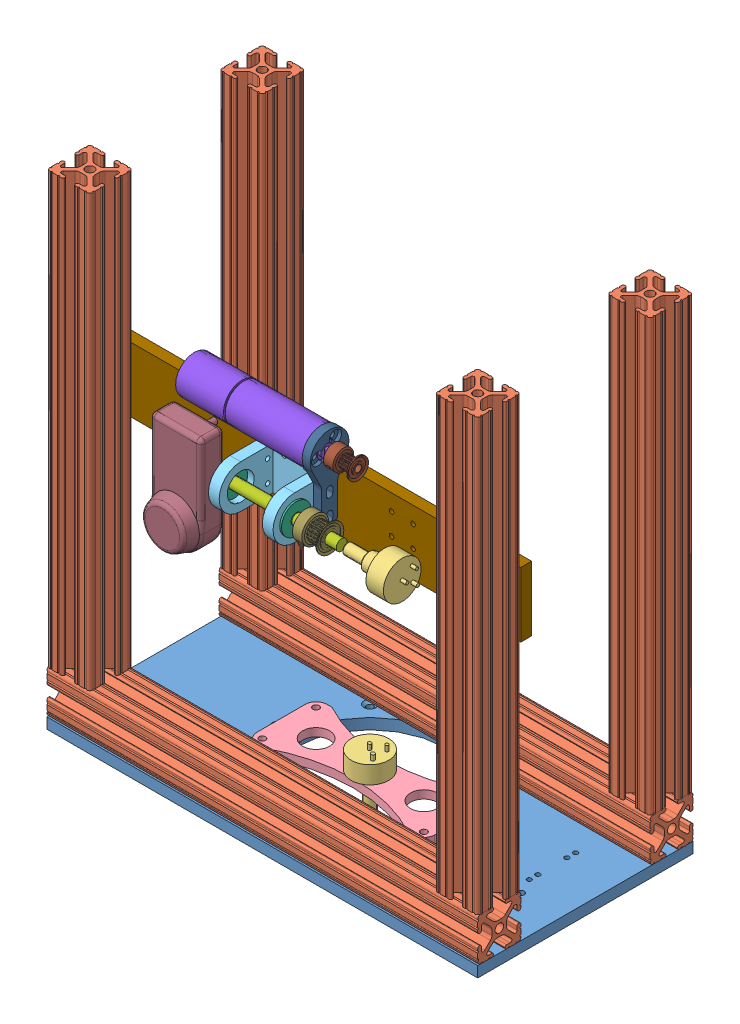
SolidWorks assembly body-frame, configuration Default. Lengths in mm.
Overall size (254 296.86 139.7).
21 component instances, 13 part files, 26 mates.
Components (placement in the parent):
- y01body-bottom-1: y01body-bottom [Default] at origin size (254 6.35 127)
- 80-20-10in-1: 80-20-10in [Default] at (-127 6.35 63.5) x (0 0 -1) z (1 0 0) size (25.4 25.4 254)
- 80-20-10in-2: 80-20-10in [Default] at (127 6.35 -63.5) x (0 0 1) z (-1 0 0) size (25.4 25.4 254)
- 80-20-10in-3: 80-20-10in [Default] at (-127 31.75 38.1) x (0 0 1) z (0 1 0) size (25.4 25.4 254)
- 80-20-10in-4: 80-20-10in [Default] at (-127 31.75 -38.1) x (1 0 0) z (0 1 0) size (25.4 25.4 254)
- 80-20-10in-5: 80-20-10in [Default] at (127 31.75 63.5) x (0 0 -1) z (0 1 0) size (25.4 25.4 254)
- 80-20-10in-6: 80-20-10in [Default] at (101.6 31.75 -38.1) x (1 0 0) z (0 1 0) size (25.4 25.4 254)
- bourns-6639-1: bourns-6639 [Default] at (0 21.4249 0) x (0 1 0) z (0 0 1) size (35.71 22.23 22.23)
- y13-pot-holder-1: y13-pot-holder [Default] at (0 6.35 0) size (104.77 4.76 41.27)
- NECK_YOKE_ASM-1: NECK_YOKE_ASM [Default] at (0 180.975 38.1) x (0 -1 0) z (-1 0 0) size (86.8 44.45 254)
  - n01-yoke-1: n01-yoke [Default] at origin size (28.53 38.1 38.1)
  - 000_rb-p25xp625-57155K324mcm-1: 000_rb-p25xp625-57155K324mcm [Default] at (0 25.4 -16.51) x (0 0 1) z (-0.947787 -0.318905 0) size (3.61 17.53 17.53)
  - 000_rb-p25xp625-57155K324mcm-2: 000_rb-p25xp625-57155K324mcm [Default] at (0 25.4 16.51) x (0 0 -1) z (0.870377 -0.492386 0) size (3.61 17.53 17.53)
  - n02-neck-pitch-shaft-1: n02-neck-pitch-shaft [Default] at (0 25.4 -11.8618) x (0.984383 -0.176038 0) z (0 0 1) size (6.34 6.34 69.85)
  - bourns-6639-1: bourns-6639 [Default] at (0 25.4 -82.4992) x (0 0 -1) z (0.999946 -0.010393 0) size (35.71 22.23 22.23)
  - MAXON-amax22-n-gear143991-1: MAXON-amax22-n-gear143991 [Default] at (-27.94 9.525 26.75) x (0 0 1) z (-1 0 0) size (89.5 22 22)
  - n03-neck-baseplate-to-body-1: n03-neck-baseplate-to-body [Default] at (3.175 0 0) x (0 0 -1) z (0 -1 0) size (254 38.1 6.35)
  - n04-motor-mount-1: n04-motor-mount [Default] at (-27.94 9.525 -19.05) x (-1 0 0) z (0 0 -1) size (49.53 22.86 4.76)
  - a_6d16m012df6003-3mm-bored-to-4mm-1: a_6d16m012df6003-3mm-bored-to-4mm [Default] at (-27.94 9.525 -32.3525) size (12.2 12.2 14.3)
  - a_6d16-018df2508-2: a_6d16-018df2508 [Default] at (0 25.4 -31.6681) x (0.999994 -0.003333 0) z (0 0 1) size (16.13 16.13 14.29)
  - LOGITECH_USB_CAM-1: LOGITECH_USB_CAM [Default] at (32.385 15.875 46.7995) x (0 0 -1) z (0 1 0) size (30.1 63.31 29.21)
Mates (geometry in assembly coordinates):
- Coincident1: coincident aligned: plane of y01body-bottom-1 through (-127 6.35 -63.5) normal (0 1 0); plane of 80-20-10in-1 through (-127 6.35 63.5) normal (0 1 0)
- Coincident2: coincident aligned: plane of 80-20-10in-1 through (-127 6.35 63.5) normal (0 1 0); plane of 80-20-10in-2 through (127 6.35 -63.5) normal (0 1 0)
- Coincident3: coincident aligned: plane of 80-20-10in-1 through (127 9.5516 63.5) normal (0 0 1); plane of y01body-bottom-1 through (-127 6.35 63.5) normal (0 0 1)
- Coincident4: coincident aligned: plane of y01body-bottom-1 through (-127 6.35 -63.5) normal (0 0 -1); plane of 80-20-10in-2 through (-127 28.5484 -63.5) normal (0 0 -1)
- Coincident5: coincident aligned: plane of y01body-bottom-1 through (127 6.35 -63.5) normal (1 0 0); plane of 80-20-10in-2 through (127 7.3801 -46.3972) normal (1 0 0)
- Coincident6: coincident aligned: plane of 80-20-10in-1 through (127 7.3801 46.3972) normal (1 0 0); plane of 80-20-10in-2 through (127 7.3801 -46.3972) normal (1 0 0)
- Coincident7: coincident anti-aligned: plane of 80-20-10in-1 through (127 31.75 57.1353) normal (0 1 0); plane of 80-20-10in-5 through (125.9699 31.75 46.3972) normal (0 -1 0)
- Coincident8: coincident aligned: plane of 80-20-10in-5 through (125.9699 31.75 46.3972) normal (0 -1 0); plane of 80-20-10in-6 through (118.7028 31.75 -39.1301) normal (0 -1 0)
- Coincident9: coincident aligned: plane of 80-20-10in-3 through (-125.9699 31.75 55.2028) normal (0 -1 0); plane of 80-20-10in-5 through (125.9699 31.75 46.3972) normal (0 -1 0)
- Coincident10: coincident aligned: plane of 80-20-10in-4 through (-109.8972 31.75 -39.1301) normal (0 -1 0); plane of 80-20-10in-5 through (125.9699 31.75 46.3972) normal (0 -1 0)
- Coincident11: coincident aligned: plane of y01body-bottom-1 through (127 6.35 -63.5) normal (1 0 0); plane of 80-20-10in-5 through (127 285.75 57.1353) normal (1 0 0)
- Coincident12: coincident aligned: plane of y01body-bottom-1 through (127 6.35 -63.5) normal (1 0 0); plane of 80-20-10in-6 through (127 285.75 -41.3016) normal (1 0 0)
- Coincident13: coincident aligned: plane of y01body-bottom-1 through (-127 6.35 -63.5) normal (0 0 -1); plane of 80-20-10in-6 through (120.6353 285.75 -63.5) normal (0 0 -1)
- Coincident14: coincident aligned: plane of 80-20-10in-4 through (-120.6353 285.75 -63.5) normal (0 0 -1); plane of 80-20-10in-6 through (120.6353 285.75 -63.5) normal (0 0 -1)
- Coincident15: coincident aligned: plane of y01body-bottom-1 through (-127 6.35 -63.5) normal (-1 0 0); plane of 80-20-10in-4 through (-127 285.75 -60.2984) normal (-1 0 0)
- Coincident16: coincident aligned: plane of y01body-bottom-1 through (-127 6.35 -63.5) normal (-1 0 0); plane of 80-20-10in-3 through (-127 285.75 44.4647) normal (-1 0 0)
- Coincident17: coincident aligned: plane of y01body-bottom-1 through (-127 6.35 63.5) normal (0 0 1); plane of 80-20-10in-3 through (-123.7984 285.75 63.5) normal (0 0 1)
- Coincident18: coincident aligned: plane of y01body-bottom-1 through (-127 6.35 63.5) normal (0 0 1); plane of 80-20-10in-5 through (123.7984 285.75 63.5) normal (0 0 1)
- Concentric1: concentric aligned: cylinder of y01body-bottom-1; cylinder of y13-pot-holder-1
- Coincident19: coincident anti-aligned: plane of y01body-bottom-1 through (-127 6.35 -63.5) normal (0 1 0); plane of y13-pot-holder-1 through (-52.3875 6.35 20.6375) normal (0 -1 0)
- Concentric2: concentric aligned: cylinder of y01body-bottom-1; cylinder of y13-pot-holder-1
- Concentric3: concentric anti-aligned: cylinder of bourns-6639-1; cylinder of y13-pot-holder-1
- Coincident20: coincident anti-aligned: plane of bourns-6639-1 through (-11.1125 11.1125 0) normal (0 -1 0); plane of y13-pot-holder-1 through (-52.3875 11.1125 20.6375) normal (0 1 0)
- Coincident21: coincident anti-aligned: plane of 80-20-10in-3; plane of NECK_YOKE_ASM-1/n03-neck-baseplate-to-body-1 through (-127 196.85 38.1) normal (0 0 1)
- Coincident22: coincident aligned: plane of 80-20-10in-3; plane of NECK_YOKE_ASM-1/n03-neck-baseplate-to-body-1 through (-127 158.75 31.75) normal (-1 0 0)
- Distance1: distance = 152.4 mm anti-aligned: plane of y01body-bottom-1 through (-127 6.35 -63.5) normal (0 1 0); plane of NECK_YOKE_ASM-1/n03-neck-baseplate-to-body-1 through (-127 158.75 31.75) normal (0 -1 0)
